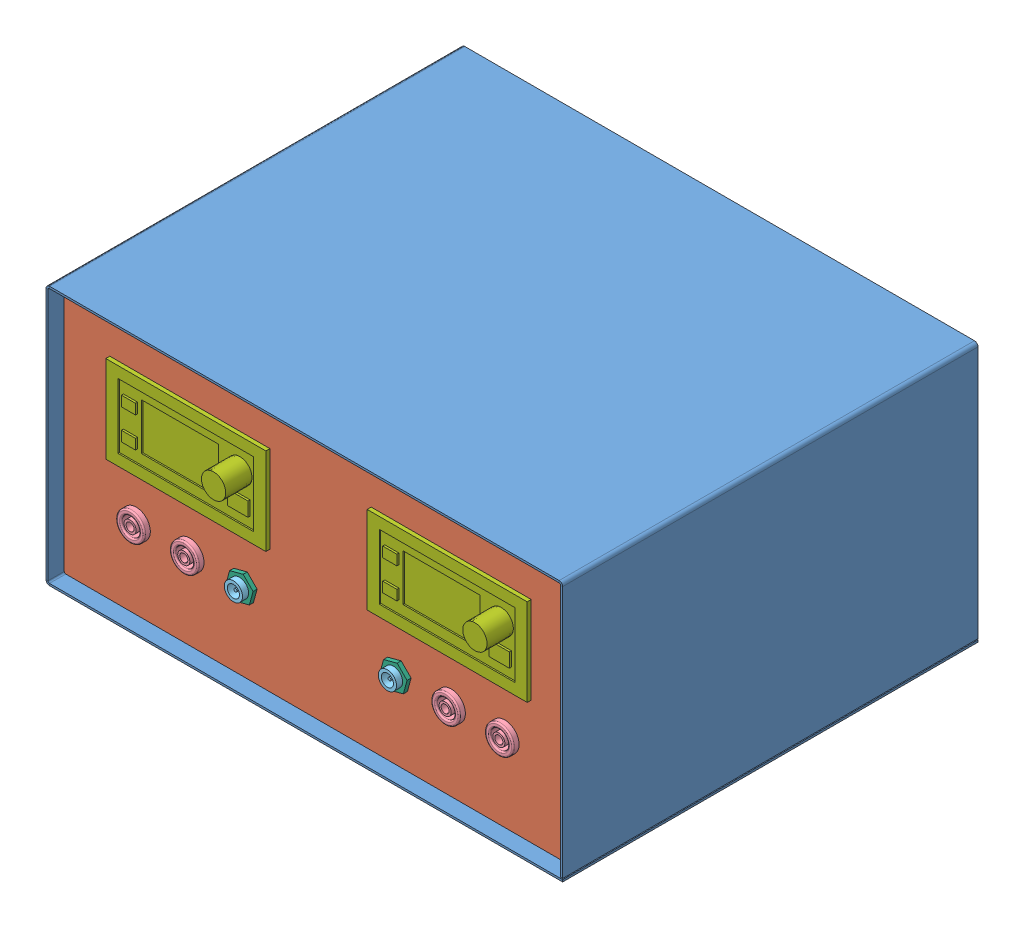
SolidWorks assembly ASSEM_POWER-SUPPLY_2, configuration Default. Lengths in mm.
Overall size (255 128 211.3).
91 component instances, 21 part files, 31 mates.
Components (placement in the parent):
- ENCLOSURE_BASE_1-1: ENCLOSURE_BASE_1 [Default] at (71.75 85.7821 197.4279) size (255 128 205)
- ENCLOSURE_FRONT_1-1: ENCLOSURE_FRONT_1 [Default] at (71.75 148.7821 291.9279) size (253 126 1)
- ENCLOSURE_BACK_1-1: ENCLOSURE_BACK_1 [Default] at (71.75 148.7821 102.9279) x (-1 0 0) z (0 0 -1) size (253 126 1)
- BANANA_PLUG_1-1: BANANA_PLUG_1 [Default] at (-19.25 124.7821 291.9279) size (14 14 30)
- BANANA_PLUG_1-2: BANANA_PLUG_1 [Default] at (7.25 124.7821 291.9279) size (14 14 30)
- JACK_DC-POWER_1-1: JACK_DC-POWER_1 [Default] at (33.75 124.7821 290.9279) size (11 13 20)
- JACK_DC-POWER_NUT_1-1: JACK_DC-POWER_NUT_1 [Default] at (33.75 124.7821 291.9279) size (13.39 13.38 2)
- ASSEM_SK35H-5: ASSEM_SK35H [Default] at (55.8819 171.8806 167.4314) size (79 43 47.3)
  - FRONT_PANEL_1-1: FRONT_PANEL_1 [Default] at (-88.1318 -25.0985 124.4964) x (1 0 0) z (0 -1 0) size (79 47.3 43)
- ASSEM_SK35H-6: ASSEM_SK35H [Default] at (184.8819 171.8806 167.4314) size (79 43 47.3)
  - FRONT_PANEL_1-1: FRONT_PANEL_1 [Default] at (-88.1318 -25.0985 124.4964) x (1 0 0) z (0 -1 0) size (79 47.3 43)
- JACK_DC-POWER_1-2: JACK_DC-POWER_1 [Default] at (109.75 124.7821 290.9279) size (11 13 20)
- JACK_DC-POWER_NUT_1-2: JACK_DC-POWER_NUT_1 [Default] at (109.75 124.7821 291.9279) size (13.39 13.38 2)
- BANANA_PLUG_1-3: BANANA_PLUG_1 [Default] at (136.25 124.7821 291.9279) size (14 14 30)
- BANANA_PLUG_1-4: BANANA_PLUG_1 [Default] at (162.75 124.7821 291.9279) x (1 0.000289 0) z (0 0 1) size (14 14 30)
- AC_SOCKET-SWITCH-FUSE_1-1: AC_SOCKET-SWITCH-FUSE_1 [Default] at (-9.25 165.7821 102.9279) x (-1 0 0) z (0 0 -1) size (31 50 23)
- POWER_SUPPLY_PAIRED.step-1: POWER_SUPPLY_PAIRED.step [Default] at (174.094 96.3705 259.2051) x (0 0 -1) z (0 1 0) size (87 207 40.41)
  - Board.step-1: Board.step [Default] at origin size (87 207 0.41)
    - Open CASCADE STEP translator 6.8 2.1.1.step-1: Open CASCADE STEP translator 6.8 2.1.1.step [Default] at (0 0 -0.4115) size (87 207 0.41)
  - X10.step-1: X10.step [Default] at origin size (1 8.2 8)
    - 8026967568.step-1: 8026967568.step [Default] at (64 196 0) size (1 8.2 1)
      - Extruded.step-1: Extruded.step [Default] at origin size (1 8.2 1)
    - 8026967408.step-1: 8026967408.step [Default] at (64 196 1) size (1 6.32 7)
      - Extruded-0.step-1: Extruded-0.step [Default] at origin size (1 6.32 7)
  - X9.step-1: X9.step [Default] at origin size (1 8.2 8)
    - 8026967568.step-1: 8026967568.step [Default] at (23 196 0) size (1 8.2 1)
      - Extruded.step-1: Extruded.step [Default] at origin size (1 8.2 1)
    - 8026967408.step-1: 8026967408.step [Default] at (23 196 1) size (1 6.32 7)
      - Extruded-0.step-1: Extruded-0.step [Default] at origin size (1 6.32 7)
  - X4.step-1: X4.step [Default] at origin size (1 8.2 8)
    - 8026967568.step-1: 8026967568.step [Default] at (62 12.8 0) size (1 8.2 1)
      - Extruded.step-1: Extruded.step [Default] at origin size (1 8.2 1)
    - 8026967408.step-1: 8026967408.step [Default] at (62 12.8 1) size (1 6.32 7)
      - Extruded-0.step-1: Extruded-0.step [Default] at origin size (1 6.32 7)
  - X3.step-1: X3.step [Default] at origin size (1 8.2 8)
    - 8026967568.step-1: 8026967568.step [Default] at (50 12.8 0) size (1 8.2 1)
      - Extruded.step-1: Extruded.step [Default] at origin size (1 8.2 1)
    - 8026967408.step-1: 8026967408.step [Default] at (50 12.8 1) size (1 6.32 7)
      - Extruded-0.step-1: Extruded-0.step [Default] at origin size (1 6.32 7)
  - X2.step-1: X2.step [Default] at origin size (1 8.2 8)
    - 8026967568.step-1: 8026967568.step [Default] at (25 12.8 0) size (1 8.2 1)
      - Extruded.step-1: Extruded.step [Default] at origin size (1 8.2 1)
    - 8026967408.step-1: 8026967408.step [Default] at (25 12.8 1) size (1 6.32 7)
      - Extruded-0.step-1: Extruded-0.step [Default] at origin size (1 6.32 7)
  - X1.step-1: X1.step [Default] at origin size (1 8.2 8)
    - 8026967568.step-1: 8026967568.step [Default] at (37.5 12.8 0) size (1 8.2 1)
      - Extruded.step-1: Extruded.step [Default] at origin size (1 8.2 1)
    - 8026967408.step-1: 8026967408.step [Default] at (37.5 12.8 1) size (1 6.32 7)
      - Extruded-0.step-1: Extruded-0.step [Default] at origin size (1 6.32 7)
  - V1.step-1: V1.step [Default] at origin size (9 4.4 9.5)
    - 8863552528.step-1: 8863552528.step [Default] at (50.5 190.3 5) x (0 0 -1) z (0 1 0) size (9 9 4.4)
      - Cylinder.step-1: Cylinder.step [Default] at origin size (9 9 4.4)
    - 21321856.step-1: 21321856.step [Default] at (53 193.3 0) x (-1 0 0) z (0 0 1) size (0.6 0.6 1.5)
      - Cylinder-1.step-1: Cylinder-1.step [Default] at origin size (0.6 0.6 1.5)
    - 21321856.step-2: 21321856.step [Default] at (48 191.7 0) x (-1 0 0) z (0 0 1) size (0.6 0.6 1.5)
      - Cylinder-1.step-1: Cylinder-1.step [Default] at origin size (0.6 0.6 1.5)
  - TR1.step-1: TR1.step [Default] at origin size (63.5 79.2 27)
    - 8024605984.step-1: 8024605984.step [Default] at (43.74 145.909 7) size (63.5 55.4 20)
      - Extruded-2.step-1: Extruded-2.step [Default] at origin size (63.5 55.4 20)
    - 8024605824.step-1: 8024605824.step [Default] at (43.74 145.909 7) size (47.48 79.2 13)
      - Extruded-3.step-1: Extruded-3.step [Default] at origin size (47.48 79.2 13)
    - 8024605664.step-1: 8024605664.step [Default] at (43.74 145.909 0) size (63.5 66 7)
      - Extruded-4.step-1: Extruded-4.step [Default] at origin size (63.5 66 7)
  - F1.step-1: F1.step [Default] at origin size (8.4 4 8.2)
    - 4370038336.step-1: 4370038336.step [Default] at (34.5 192.5 0) size (8.4 4 8.2)
      - Extruded-5.step-1: Extruded-5.step [Default] at origin size (8.4 4 8.2)
  - C6.step-1: C6.step [Default] at origin size (18 18 40)
    - 8024605344.step-1: 8024605344.step [Default] at (55.08 33.274 0) x (-1 0 0) z (0 0 1) size (18 18 40)
      - Cylinder-6.step-1: Cylinder-6.step [Default] at origin size (18 18 40)
  - C5.step-1: C5.step [Default] at origin size (18 18 40)
    - 8024605344.step-1: 8024605344.step [Default] at (55.08 56.261 0) x (-1 0 0) z (0 0 1) size (18 18 40)
      - Cylinder-6.step-1: Cylinder-6.step [Default] at origin size (18 18 40)
  - C4.step-1: C4.step [Default] at origin size (18 18 40)
    - 8024605344.step-1: 8024605344.step [Default] at (55.08 79.248 0) x (-1 0 0) z (0 0 1) size (18 18 40)
      - Cylinder-6.step-1: Cylinder-6.step [Default] at origin size (18 18 40)
  - C3.step-1: C3.step [Default] at origin size (18 18 40)
    - 8026966928.step-1: 8026966928.step [Default] at (32.516 33.274 0) x (1 0 0) z (0 0 1) size (18 18 40)
      - Cylinder-7.step-1: Cylinder-7.step [Default] at origin size (18 18 40)
  - C2.step-1: C2.step [Default] at origin size (18 18 40)
    - 8026966928.step-1: 8026966928.step [Default] at (32.523 56.261 0) x (1 0 0) z (0 0 1) size (18 18 40)
      - Cylinder-7.step-1: Cylinder-7.step [Default] at origin size (18 18 40)
  - C1.step-1: C1.step [Default] at origin size (18 18 40)
    - 8026966928.step-1: 8026966928.step [Default] at (32.523 79.248 0) x (1 0 0) z (0 0 1) size (18 18 40)
      - Cylinder-7.step-1: Cylinder-7.step [Default] at origin size (18 18 40)
  - BR2.step-1: BR2.step [Default] at origin size (19 8.1 15.8)
    - 8026967088.step-1: 8026967088.step [Default] at (57.9 97.15 0) size (19 8.1 15.8)
      - Extruded-8.step-1: Extruded-8.step [Default] at origin size (19 8.1 15.8)
  - BR1.step-1: BR1.step [Default] at origin size (19 8.1 15.8)
    - 8026967088.step-1: 8026967088.step [Default] at (29.6 97.15 0) size (19 8.1 15.8)
      - Extruded-8.step-1: Extruded-8.step [Default] at origin size (19 8.1 15.8)
- FILTER_BOX_FN2020-10-06-1: FILTER_BOX_FN2020-10-06 [Default] at (-3.8509 98.646 138.7864) x (-1 0 0) z (0 0 -1) size (50.5 29.3 63.05)
Mates (geometry in assembly coordinates):
- Coincident1: coincident anti-aligned: plane of ENCLOSURE_BASE_1-1 through (198.25 85.7821 197.4279) normal (-1 0 0); plane of ENCLOSURE_FRONT_1-1 through (198.25 211.7821 290.9279) normal (1 0 0)
- Coincident2: coincident anti-aligned: plane of ENCLOSURE_BASE_1-1 through (71.75 85.7821 197.4279) normal (0 1 0); plane of ENCLOSURE_FRONT_1-1 through (-54.75 85.7821 290.9279) normal (0 -1 0)
- Coincident3: coincident aligned: line of ENCLOSURE_FRONT_1-1 through (-54.75 85.7821 291.9279) axis (1 0 0)
- Coincident4: coincident anti-aligned: plane of ENCLOSURE_BASE_1-1 through (-54.75 85.7821 197.4279) normal (1 0 0); plane of ENCLOSURE_BACK_1-1 through (-54.75 211.7821 103.9279) normal (-1 0 0)
- Coincident5: coincident anti-aligned: plane of ENCLOSURE_BASE_1-1 through (71.75 85.7821 197.4279) normal (0 1 0); plane of ENCLOSURE_BACK_1-1 through (198.25 85.7821 103.9279) normal (0 -1 0)
- Coincident6: coincident anti-aligned: line of ENCLOSURE_BACK_1-1 through (198.25 85.7821 102.9279) axis (-1 0 0)
- Coincident19: coincident anti-aligned: plane of ENCLOSURE_FRONT_1-1 through (71.75 148.7821 291.9279) normal (0 0 1); plane of ASSEM_SK35H-5/FRONT_PANEL_1-1 through (-32.25 146.7821 291.9279) normal (0 0 -1)
- Coincident20: coincident: plane of ASSEM_SK35H-5/FRONT_PANEL_1-1 through (-32.25 189.7821 293.9279) normal (0 1 0)
- Coincident21: coincident: plane of ASSEM_SK35H-5/FRONT_PANEL_1-1 through (-32.25 146.7821 293.9279) normal (-1 0 0)
- Coincident22: coincident anti-aligned: plane of ENCLOSURE_FRONT_1-1 through (71.75 148.7821 291.9279) normal (0 0 1); plane of ASSEM_SK35H-6/FRONT_PANEL_1-1 through (96.75 146.7821 291.9279) normal (0 0 -1)
- Coincident23: coincident: plane of ASSEM_SK35H-6/FRONT_PANEL_1-1 through (175.75 146.7821 293.9279) normal (1 0 0)
- Coincident25: coincident: plane of ASSEM_SK35H-6/FRONT_PANEL_1-1 through (96.75 189.7821 293.9279) normal (0 1 0)
- Coincident26: coincident anti-aligned: plane of ENCLOSURE_FRONT_1-1 through (71.75 148.7821 291.9279) normal (0 0 1); plane of BANANA_PLUG_1-1 through (-19.25 124.7821 291.9279) normal (0 0 -1)
- Concentric1: concentric: cylinder of BANANA_PLUG_1-1 through (-19.25 124.7821 284.9279) axis (0 0 1) radius 2
- Coincident29: coincident anti-aligned: plane of ENCLOSURE_FRONT_1-1 through (71.75 148.7821 291.9279) normal (0 0 1); plane of BANANA_PLUG_1-2 through (7.25 124.7821 291.9279) normal (0 0 -1)
- Concentric2: concentric: cylinder of BANANA_PLUG_1-2 through (7.25 124.7821 284.9279) axis (0 0 1) radius 2
- Coincident31: coincident anti-aligned: plane of ENCLOSURE_FRONT_1-1 through (71.75 148.7821 290.9279) normal (0 0 -1); plane of JACK_DC-POWER_1-1 through (28.75 119.2821 290.9279) normal (0 0 1)
- Concentric3: concentric: cylinder of JACK_DC-POWER_1-1 through (33.75 124.7821 291.9279) axis (0 0 1) radius 3
- Coincident34: coincident anti-aligned: plane of ENCLOSURE_FRONT_1-1 through (71.75 148.7821 291.9279) normal (0 0 1); plane of JACK_DC-POWER_NUT_1-1 through (33.75 124.7821 291.9279) normal (0 0 -1)
- Concentric4: concentric anti-aligned: cylinder of JACK_DC-POWER_1-1 through (33.75 124.7821 291.9279) axis (0 0 1) radius 3; cylinder of JACK_DC-POWER_NUT_1-1 through (33.75 124.7821 293.9279) axis (0 0 -1) radius 4.25
- Coincident36: coincident anti-aligned: plane of ENCLOSURE_FRONT_1-1 through (71.75 148.7821 290.9279) normal (0 0 -1); plane of JACK_DC-POWER_1-2 through (104.75 119.2821 290.9279) normal (0 0 1)
- Concentric6: concentric: cylinder of JACK_DC-POWER_1-2 through (109.75 124.7821 295.9279) axis (0 0 -1) radius 0.75
- Coincident39: coincident anti-aligned: plane of ENCLOSURE_FRONT_1-1 through (71.75 148.7821 291.9279) normal (0 0 1); plane of JACK_DC-POWER_NUT_1-2 through (109.75 124.7821 291.9279) normal (0 0 -1)
- Concentric7: concentric anti-aligned: cylinder of JACK_DC-POWER_1-2 through (109.75 124.7821 291.9279) axis (0 0 1) radius 3; cylinder of JACK_DC-POWER_NUT_1-2 through (109.75 124.7821 293.9279) axis (0 0 -1) radius 4.25
- Coincident40: coincident anti-aligned: plane of ENCLOSURE_FRONT_1-1 through (71.75 148.7821 291.9279) normal (0 0 1); plane of BANANA_PLUG_1-3 through (136.25 124.7821 291.9279) normal (0 0 -1)
- Concentric8: concentric: cylinder of BANANA_PLUG_1-3 through (136.25 124.7821 284.9279) axis (0 0 1) radius 2
- Coincident42: coincident anti-aligned: plane of ENCLOSURE_FRONT_1-1 through (71.75 148.7821 291.9279) normal (0 0 1); plane of BANANA_PLUG_1-4 through (162.75 124.7821 291.9279) normal (0 0 -1)
- Concentric9: concentric: cylinder of BANANA_PLUG_1-4 through (162.75 124.7821 284.9279) axis (0 0 1) radius 2
- Coincident43: coincident anti-aligned: plane of ENCLOSURE_BACK_1-1 through (71.75 148.7821 102.9279) normal (0 0 -1); plane of AC_SOCKET-SWITCH-FUSE_1-1 through (-22.75 142.7821 102.9279) normal (0 0 1)
- Coincident44: coincident: plane of AC_SOCKET-SWITCH-FUSE_1-1 through (4.25 190.7821 99.9279) normal (0 1 0)
- Coincident45: coincident: plane of AC_SOCKET-SWITCH-FUSE_1-1 through (-24.75 188.7821 99.9279) normal (-1 0 0)
